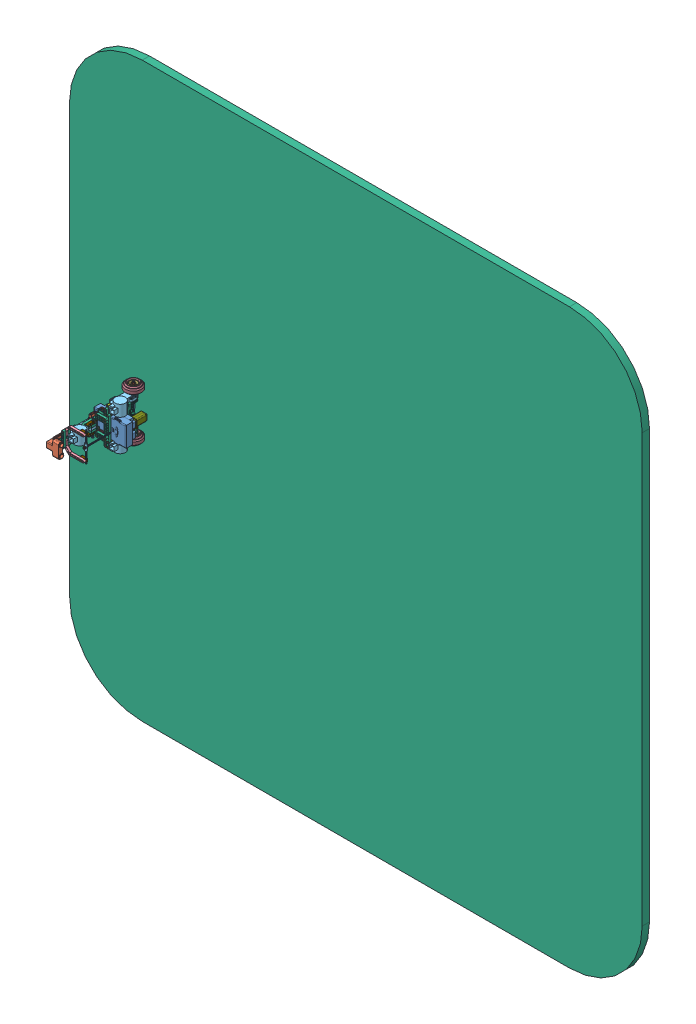
SolidWorks assembly Segway assembly, configuration Default. Lengths in mm.
Overall size (2000 2000 305.82).
138 component instances, 24 part files, 47 mates.
Components (placement in the parent):
- CPU-1: CPU [Default] at (208.205 65.6527 -35.0694) x (1 0 0) z (0 0 1) size (111.76 70.87 40)
- right_connector-1: right_connector [Default] at (170.132 77.851 -11.684) x (0 1 0) z (1 0 0) size (23.11 39.12 23.37)
  - L_Three_Five_90degrees-1: L_Three_Five_90degrees [Default] x (0 1 0) z (-1 0 0) size (39.12 23.37 7.87)
  - BlackConnectorSmall-1: BlackConnectorSmall [Default] at (0 7.874 0) x (-1 0 0) z (0 0 -1) size (15.24 5.59 5.59)
  - BlackConnectorSmall-2: BlackConnectorSmall [Default] at (7.874 -23.622 0) x (-1 0 0) z (0 0 -1) size (15.24 5.59 5.59)
  - BlueConnectorLong-1: BlueConnectorLong [Default] at (7.874 -7.874 0) x (-1 0 0) z (0 0 -1) size (22.86 5.59 5.59)
- left_connector-1: left_connector [Default] at (170.132 -0.889 -11.684) x (0 1 0) z (1 0 0) size (23.11 39.12 23.37)
  - L_Three_Five_90degrees-1: L_Three_Five_90degrees [Default] x (0 1 0) z (-1 0 0) size (39.12 23.37 7.87)
  - BlackConnectorSmall-1: BlackConnectorSmall [Default] at (-7.366 7.874 0) size (15.24 5.59 5.59)
  - BlackConnectorSmall-2: BlackConnectorSmall [Default] at (-15.24 -23.622 0) size (15.24 5.59 5.59)
  - BlueConnectorLong-1: BlueConnectorLong [Default] at (-15.24 -7.874 0) size (22.86 5.59 5.59)
- Motor-1: Motor [Default] at (170.132 -24.257 -19.558) x (0 0 1) z (1 0 0) size (103.9 39.37 46.48)
- Motor-2: Motor [Default] at (170.132 85.979 -19.558) x (0 0 1) z (1 0 0) size (103.9 39.37 46.48)
- horizontal_connector-1: horizontal_connector [Default] at (185.88 34.798 0.127) x (0 1 0) z (1 0 0) size (133.6 31.24 39.12)
  - All_Straight-1: All_Straight [Eleven] at (31.496 0 0) x (1 0 0) z (0 1 0) size (86.36 7.62 7.87)
  - BlackConnectorSmall-1: BlackConnectorSmall [Default] at (39.37 7.62 0) x (0 -1 0) z (0 0 1) size (15.24 5.59 5.59)
  - BlackConnectorSmall-2: BlackConnectorSmall [Default] at (-39.37 7.62 0) x (0 -1 0) z (0 0 1) size (15.24 5.59 5.59)
  - BlackConnectorSmall-4: BlackConnectorSmall [Default] at (-23.622 0.254 0) x (0 1 0) z (0 0 -1) size (15.24 5.59 5.59)
  - BlackConnectorSmall-5: BlackConnectorSmall [Default] at (23.622 0.254 0) x (0 1 0) z (0 0 -1) size (15.24 5.59 5.59)
  - L_Two_Four_90degrees-1: L_Two_Four_90degrees [Default] at (47.4776 -6.6697 -16.0899) x (1 0 0) z (0 -1 0) size (31.24 15.49 7.87)
  - L_Two_Four_90degrees-3: L_Two_Four_90degrees [Default] at (-47.4776 -1.2043 -16.0899) x (-1 0 0) z (0 1 0) size (31.24 15.49 7.87)
  - BlackConnectorSmall-6: BlackConnectorSmall [Default] at (-39.37 -7.62 -7.874) x (0 1 0) z (0 0 -1) size (15.24 5.59 5.59)
  - BlackConnectorSmall-7: BlackConnectorSmall [Default] at (39.37 -7.62 -7.874) x (0 1 0) z (0 0 -1) size (15.24 5.59 5.59)
  - BlueConnectorLong-1: BlueConnectorLong [Default] at (47.244 7.62 -7.874) x (0 -1 0) z (-1 0 0) size (22.86 5.59 5.59)
  - BlueConnectorLong-2: BlueConnectorLong [Default] at (55.118 7.62 -7.874) x (0 -1 0) z (-1 0 0) size (22.86 5.59 5.59)
  - BlueConnectorLong-3: BlueConnectorLong [Default] at (-47.244 7.62 -7.874) x (0 -1 0) z (0 0 1) size (22.86 5.59 5.59)
  - BlueConnectorLong-4: BlueConnectorLong [Default] at (-55.118 7.62 -7.874) x (0 -1 0) z (0 0 1) size (22.86 5.59 5.59)
  - All_Straight-3: All_Straight [Fifteen] at (47.244 0 -7.874) x (1 0 0) z (0 1 0) size (117.86 7.62 7.87)
  - BlackConnectorSmall-8: BlackConnectorSmall [Default] at (23.622 0.254 -7.874) x (0 1 0) z (0 0 -1) size (15.24 5.59 5.59)
  - BlackConnectorSmall-9: BlackConnectorSmall [Default] at (-23.622 0.254 -7.874) x (0 1 0) z (0 0 -1) size (15.24 5.59 5.59)
  - All_Straight-4: All_Straight [Five] at (-23.622 15.748 -7.874) x (0 0 1) z (0 -1 0) size (39.12 7.62 7.87)
  - All_Straight-5: All_Straight [Five] at (23.622 15.748 -7.874) x (0 0 1) z (0 -1 0) size (39.12 7.62 7.87)
  - BlueConnectorCross_Tube-1: BlueConnectorCross_Tube [Default] at (62.992 -7.874 -7.874) x (0 -1 0) z (0 0 1) size (15.24 5.08 5.08)
  - BlueConnectorCross_Tube-2: BlueConnectorCross_Tube [Default] at (-62.992 -7.874 -7.874) x (0 -1 0) z (0 0 -1) size (15.24 5.08 5.08)
- Rotor-1: Rotor [Default] at (178.006 97.155 -90.424) x (-0.695581 0 -0.718448) z (0 1 0) size (23.62 23.62 23.66)
- Rotor-2: Rotor [Default] at (178.006 -13.081 -90.424) x (-0.059852 0 -0.998207) z (0 1 0) size (23.62 23.62 23.66)
- wheel_and_axle-1: wheel_and_axle [Default] at (179.0661 128.27 -89.3291) x (0 -1 0) z (0.695581 0 0.718448) size (82.68 55.88 55.88)
  - CrossTemplate-1: CrossTemplate [Nine] x (0 0 -1) z (1 0 0) size (4.57 4.57 70.87)
  - Light_Gray_X8__Template-1: Light_Gray_X8__Template [one] at (2.54 0 6.35) x (0 0 -1) z (1 0 0) size (7.62 7.62 7.87)
  - Light_Gray_X12-1: Light_Gray_X12 [Rim] at (16.637 0 -9.144) x (0 0 1) z (-1 0 0) size (30.48 30.48 20.07)
  - Light_Gray_X13-1: Light_Gray_X13 [Tire] at (16.637 0 6.096) x (0 0 -1) z (1 0 0) size (55.88 55.88 25.4)
  - Light_Gray_X8__Template-2: Light_Gray_X8__Template [half] at (22.86 0 6.35) x (0 0 -1) z (1 0 0) size (7.62 7.62 3.94)
  - CrossComplementEnd_Small-1: CrossComplementEnd_Small [Three] at (59.054 0 0) x (0 0 -1) z (1 0 0) size (7.62 7.62 23.62)
- wheel_and_axle-2: wheel_and_axle [Default] at (178.0972 -58.674 -88.9027) x (0 1 0) z (0.059852 0 0.998207) size (82.68 55.88 55.88)
  - CrossTemplate-1: CrossTemplate [Nine] x (0 0 -1) z (1 0 0) size (4.57 4.57 70.87)
  - Light_Gray_X8__Template-1: Light_Gray_X8__Template [one] at (2.54 0 6.35) x (0 0 -1) z (1 0 0) size (7.62 7.62 7.87)
  - Light_Gray_X12-1: Light_Gray_X12 [Rim] at (16.637 0 -9.144) x (0 0 1) z (-1 0 0) size (30.48 30.48 20.07)
  - Light_Gray_X13-1: Light_Gray_X13 [Tire] at (16.637 0 6.096) x (0 0 -1) z (1 0 0) size (55.88 55.88 25.4)
  - Light_Gray_X8__Template-2: Light_Gray_X8__Template [half] at (22.86 0 6.35) x (0 0 -1) z (1 0 0) size (7.62 7.62 3.94)
  - CrossComplementEnd_Small-1: CrossComplementEnd_Small [Three] at (59.054 0 0) x (0 0 -1) z (1 0 0) size (7.62 7.62 23.62)
- CrossTemplate-1: CrossTemplate [Five] at (179.1009 54.483 -91.4841) x (-0.718448 0 0.695581) z (0 -1 0) size (4.57 4.57 39.37)
- lower_horizontal_connector-1: lower_horizontal_connector [Default] at (193.754 66.294 -54.991) x (0 1 0) z (1 0 0) size (117.86 51.45 29.62)
  - All_Straight-1: All_Straight [Eleven] x (1 0 0) z (0 1 0) size (86.36 7.62 7.87)
  - BlueConnectorLong-1: BlueConnectorLong [Default] at (7.874 7.493 0) x (0 -1 0) z (0 0 1) size (22.86 5.59 5.59)
  - BlueConnectorLong-2: BlueConnectorLong [Default] at (-70.866 7.493 0) x (0 -1 0) z (0 0 1) size (22.86 5.59 5.59)
  - All_Straight-2: All_Straight [Three] at (7.874 -8.001 0) x (1 0 0) z (0 1 0) size (23.37 7.62 7.87)
  - All_Straight-3: All_Straight [Three] at (-70.866 -8.001 0) x (1 0 0) z (0 1 0) size (23.37 7.62 7.87)
  - Light_Gray_X10-1: Light_Gray_X10 [Default] at (-70.866 -15.621 0) size (31.24 31.24 7.62)
  - Light_Gray_X10-3: Light_Gray_X10 [Default] at (7.874 -15.621 0) x (-1 0 0) z (0 0 -1) size (31.24 31.24 7.62)
  - Light_Gray_X10-4: Light_Gray_X10 [Default] at (-15.748 -8.001 0) size (31.24 31.24 7.62)
  - Light_sensor-1: Light_sensor [Default] at (-31.904 -21.981 14.31) x (-1 0 0) z (0 -1 0) size (22.5 29.62 43.2)
- left_rider_bottom-1: left_rider_bottom [Default] at (142.573 19.05 43.434) x (0 1 0) z (1 0 0) size (39.12 54.99 54.99)
  - All_Straight-1: All_Straight [Seven] x (0 1 0) z (0 0 1) size (54.86 7.62 7.87)
  - BlackConnectorSmall-1: BlackConnectorSmall [Default] at (0 0 15.494) x (0 0 -1) z (1 0 0) size (15.24 5.59 5.59)
  - BlackConnectorSmall-3: BlackConnectorSmall [Default] at (0 -7.874 15.494) x (0 0 -1) z (1 0 0) size (15.24 5.59 5.59)
  - BlackConnectorSmall-4: BlackConnectorSmall [Default] at (0 -23.622 -7.62) x (0 0 1) z (1 0 0) size (15.24 5.59 5.59)
  - BlackConnectorSmall-5: BlackConnectorSmall [Default] at (0 -39.37 -7.62) x (0 0 1) z (1 0 0) size (15.24 5.59 5.59)
  - Light_Gray_X1-1: Light_Gray_X1 [Default] at (3.937 -31.496 -3.937) x (0 1 0) z (0 0 1) size (23.62 23.11 7.87)
  - StraightTurn_Twohole_1Cross-1: StraightTurn_Twohole_1Cross [Default] at (3.81 -7.747 11.811) x (0 -1 0) z (-1 0 0) size (23.5 7.87 7.87)
  - L_Three_Five_90degrees-1: L_Three_Five_90degrees [Default] at (-11.557 -39.37 3.937) x (0 0 -1) z (1 0 0) size (39.12 23.37 7.87)
  - Light_Gray_X1-2: Light_Gray_X1 [Default] at (-19.685 -39.37 19.685) x (0 0 -1) z (0 -1 0) size (23.62 23.11 7.87)
  - BlueConnectorLong-1: BlueConnectorLong [Default] at (-27.305 -39.37 19.685) size (22.86 5.59 5.59)
  - BlackConnectorSmall-6: BlackConnectorSmall [Default] at (-15.748 -27.813 11.811) x (0 -1 0) z (0 0 1) size (15.24 5.59 5.59)
  - BlackConnectorSmall-7: BlackConnectorSmall [Default] at (-15.748 -27.813 27.559) x (0 -1 0) z (0 0 1) size (15.24 5.59 5.59)
  - All_Straight-2: All_Straight [Five] at (-15.748 -35.433 19.685) x (0 0 -1) z (0 1 0) size (39.12 7.62 7.87)
  - All_Straight-3: All_Straight [Three] at (-27.559 -39.37 19.685) x (0 0 -1) z (1 0 0) size (23.37 7.62 7.87)
  - BlackConnectorSmall-8: BlackConnectorSmall [Default] at (-15.748 -43.053 35.433) x (0 1 0) z (0 0 1) size (15.24 5.59 5.59)
  - BlackConnectorSmall-9: BlackConnectorSmall [Default] at (-15.748 -43.053 43.307) x (0 1 0) z (1 0 0) size (15.24 5.59 5.59)
- right_rider_bottom-1: right_rider_bottom [Default] at (142.573 50.546 43.434) x (0 1 0) z (1 0 0) size (39.12 54.99 54.99)
  - All_Straight-1: All_Straight [Seven] x (0 1 0) z (0 0 1) size (54.86 7.62 7.87)
  - BlackConnectorSmall-1: BlackConnectorSmall [Default] at (0 0 15.494) x (0 0 -1) z (1 0 0) size (15.24 5.59 5.59)
  - BlackConnectorSmall-3: BlackConnectorSmall [Default] at (0 -7.874 15.494) x (0 0 -1) z (1 0 0) size (15.24 5.59 5.59)
  - BlackConnectorSmall-4: BlackConnectorSmall [Default] at (0 -23.622 -7.62) x (0 0 1) z (1 0 0) size (15.24 5.59 5.59)
  - BlackConnectorSmall-5: BlackConnectorSmall [Default] at (0 -39.37 -7.62) x (0 0 1) z (1 0 0) size (15.24 5.59 5.59)
  - Light_Gray_X1-1: Light_Gray_X1 [Default] at (3.937 -31.496 -3.937) x (0 1 0) z (0 0 1) size (23.62 23.11 7.87)
  - StraightTurn_Twohole_1Cross-1: StraightTurn_Twohole_1Cross [Default] at (3.81 -7.747 11.811) x (0 -1 0) z (-1 0 0) size (23.5 7.87 7.87)
  - L_Three_Five_90degrees-1: L_Three_Five_90degrees [Default] at (4.191 -39.37 3.937) x (0 0 -1) z (1 0 0) size (39.12 23.37 7.87)
  - Light_Gray_X1-2: Light_Gray_X1 [Default] at (19.685 -39.37 19.685) x (0 0 -1) z (0 1 0) size (23.62 23.11 7.87)
  - BlueConnectorLong-1: BlueConnectorLong [Default] at (27.305 -39.37 19.685) x (-1 0 0) z (0 0 -1) size (22.86 5.59 5.59)
  - BlackConnectorSmall-6: BlackConnectorSmall [Default] at (15.748 -27.813 11.811) x (0 -1 0) z (0 0 1) size (15.24 5.59 5.59)
  - BlackConnectorSmall-7: BlackConnectorSmall [Default] at (15.748 -27.813 27.559) x (0 -1 0) z (0 0 1) size (15.24 5.59 5.59)
  - All_Straight-2: All_Straight [Five] at (15.748 -35.433 19.685) x (0 0 -1) z (0 1 0) size (39.12 7.62 7.87)
  - All_Straight-3: All_Straight [Three] at (27.559 -39.37 19.685) x (0 0 -1) z (-1 0 0) size (23.37 7.62 7.87)
  - BlackConnectorSmall-8: BlackConnectorSmall [Default] at (15.748 -27.813 43.307) x (0 -1 0) z (0 0 1) size (15.24 5.59 5.59)
  - BlackConnectorSmall-9: BlackConnectorSmall [Default] at (15.748 -27.813 35.433) x (0 -1 0) z (0 0 1) size (15.24 5.59 5.59)
- Motor-3: Motor [Default] at (130.762 30.861 82.804) x (0 0 1) z (1 0 0) size (103.9 39.37 46.48)
- Rotor-3: Rotor [Default] at (138.636 42.037 11.938) x (0 0 -1) z (0 1 0) size (23.62 23.62 23.66)
- All_Straight-1: All_Straight [Three] at (154.384 22.987 27.686) x (0 0 -1) z (0 1 0) size (23.37 7.62 7.87)
- BlueConnectorLong-1: BlueConnectorLong [Default] at (154.384 23.241 35.56) x (0 1 0) z (0 0 1) size (22.86 5.59 5.59)
- BlueConnectorLong-2: BlueConnectorLong [Default] at (154.384 46.355 19.812) x (0 -1 0) z (-0.122872 0 0.992423) size (22.86 5.59 5.59)
- All_Straight-2: All_Straight [Three] at (154.384 38.735 27.686) x (0 0 1) z (0 1 0) size (23.37 7.62 7.87)
- CrossTemplateWithCap-1: CrossTemplateWithCap [Eight] at (154.384 4.318 29.21) x (0 0 -1) z (0 1 0) size (6.6 6.6 60.96)
- head-1: head [Default] at (148.2665 34.0473 137.922) x (1 0 0) z (0 -1 0) size (44.45 98.81 50.8)
  - ProximitySensor-1: ProximitySensor [Default] x (1 0 0) z (0 1 0) size (44.45 50.8 27.94)
  - BlueConnectorLong-3: BlueConnectorLong [Default] at (-17.5045 0 10.8063) x (0 0 -1) z (0 -1 0) size (22.86 5.59 5.59)
  - BlueConnectorLong-4: BlueConnectorLong [Default] at (-1.7565 0 -12.3077) x (0 0 1) z (1 0 0) size (22.86 5.59 5.59)
  - L_Three_Five_90degrees-1: L_Three_Five_90degrees [Default] at (-17.5045 -7.874 10.8063) x (0 1 0) z (0 0 -1) size (39.12 23.37 7.87)
  - L_Three_Five_90degrees-3: L_Three_Five_90degrees [Default] at (-17.5045 -7.874 -4.9417) x (0 1 0) z (0 0 -1) size (39.12 23.37 7.87)
  - BlueConnectorLong-5: BlueConnectorLong [Default] at (-17.5045 -7.874 10.8063) x (0 0 -1) z (1 0 0) size (22.86 5.59 5.59)
  - BlueConnectorLong-6: BlueConnectorLong [Default] at (-17.5045 -31.496 -12.3077) x (0 0 1) z (0 -1 0) size (22.86 5.59 5.59)
  - All_Straight-2: All_Straight [Nine] at (-17.5045 -15.748 -4.6877) x (0 1 0) z (0 0 1) size (70.61 7.62 7.87)
- CrossConnectorLong-1: CrossConnectorLong [Default] at (124.7015 15.113 87.8309) x (0.769691 0 -0.638416) z (0 1 0) size (7.62 7.62 23.62)
- CrossConnectorLong-2: CrossConnectorLong [Default] at (124.7015 15.113 72.0829) x (0.769691 0 -0.638416) z (0 1 0) size (7.62 7.62 23.62)
- arms_and_chest-1: arms_and_chest [Default] at (138.636 50.546 117.983) x (0 1 0) z (1 0 0) size (102.11 106.17 70.74)
  - All_Straight-1: All_Straight [Seven] x (1 0 0) z (0 -1 0) size (54.86 7.62 7.87)
  - BlueConnectorLong-1: BlueConnectorLong [Default] at (-39.37 -0.254 0) x (0 -1 0) z (0 0 1) size (22.86 5.59 5.59)
  - BlueConnectorLong-3: BlueConnectorLong [Default] at (7.874 -0.254 0) x (0 -1 0) z (0 0 1) size (22.86 5.59 5.59)
  - BlueConnectorCross_Tube-1: BlueConnectorCross_Tube [Default] at (-23.622 -7.874 0) x (0 1 0) z (0 0 1) size (15.24 5.08 5.08)
  - BlueConnectorCross_Tube-2: BlueConnectorCross_Tube [Default] at (-7.874 -7.874 0) x (0 1 0) z (0 0 1) size (15.24 5.08 5.08)
  - Three_Four_Seven_90degreesTurn-1: Three_Four_Seven_90degreesTurn [Default] at (-31.496 -15.494 0) x (1 0 0) z (0 1 0) size (39.12 70.61 7.62)
  - Three_Four_Seven_90degreesTurn-4: Three_Four_Seven_90degreesTurn [Default] at (0 -7.874 0) x (-1 0 0) z (0 -1 0) size (39.12 70.61 7.62)
  - All_Straight-2: All_Straight [Seven] at (0 -23.368 0) x (1 0 0) z (0 1 0) size (54.86 7.62 7.87)
  - BlackConnectorSmall-1: BlackConnectorSmall [Default] at (23.622 -7.874 47.244) x (0 -1 0) z (0 0 1) size (15.24 5.59 5.59)
  - BlackConnectorSmall-2: BlackConnectorSmall [Default] at (23.622 -7.874 55.118) x (0 -1 0) z (0 0 1) size (15.24 5.59 5.59)
  - BlackConnectorSmall-3: BlackConnectorSmall [Default] at (-55.118 -7.874 47.244) x (0 -1 0) z (0 0 1) size (15.24 5.59 5.59)
  - BlackConnectorSmall-4: BlackConnectorSmall [Default] at (-55.118 -7.874 55.118) x (0 -1 0) z (0 0 1) size (15.24 5.59 5.59)
  - BlackConnectorSmall-5: BlackConnectorSmall [Default] at (-31.496 -23.114 0) x (0 1 0) z (0 0 1) size (15.24 5.59 5.59)
  - BlackConnectorSmall-6: BlackConnectorSmall [Default] at (0 -23.114 0) x (0 1 0) z (0 0 1) size (15.24 5.59 5.59)
  - StraightTurn_Twohole_1Cross-1: StraightTurn_Twohole_1Cross [Default] at (27.432 -19.431 54.991) x (0 0 1) z (-1 0 0) size (23.5 7.87 7.87)
  - StraightTurn_Twohole_1Cross-2: StraightTurn_Twohole_1Cross [Default] at (-51.308 -19.431 54.991) x (0 0 1) z (-1 0 0) size (23.5 7.87 7.87)
  - CrossTemplate-1: CrossTemplate [Six] at (-11.938 -19.431 64.516) x (0 0 -1) z (1 0 0) size (4.57 4.57 47.24)
  - Cross_AngleHole-1: Cross_AngleHole [Default] at (-4.318 -19.431 61.468) x (0 0 1) z (-1 0 0) size (7.62 7.62 22.86)
  - CrossTemplate-2: CrossTemplate [Six] at (-66.802 -19.431 64.516) x (0 0 -1) z (1 0 0) size (4.57 4.57 47.24)
  - CrossTemplate-3: CrossTemplate [Twelve] at (-17.272 -11.684 62.992) x (1 0 0) z (0 -1 0) size (4.57 4.57 94.49)
  - Light_Gray_X8__Template-1: Light_Gray_X8__Template [half] at (-23.622 -11.684 62.992) x (1 0 0) z (0 -1 0) size (7.62 7.62 3.94)
  - BlackConnectorSmall-7: BlackConnectorSmall [Default] at (-7.874 -15.748 0) x (0 -1 0) z (0 0 1) size (15.24 5.59 5.59)
  - BlackConnectorSmall-8: BlackConnectorSmall [Default] at (-23.622 -15.748 0) x (0 -1 0) z (0 0 1) size (15.24 5.59 5.59)
- Tabletop-1: Tabletop [Default] at (-73.175 1085.5214 -118.364) x (1 0 0) z (0 1 0) size (2000 25.4 2000)
Mates (geometry in assembly coordinates):
- Hinge1: hinge anti-aligned: cylinder of right_connector-1/BlackConnectorSmall-1 through (170.132 77.851 -3.81) axis (0 1 0) radius 2.032; cylinder of CPU-1 through (170.132 62.357 -3.81) axis (0 1 0) radius 2.286; plane of CPU-1 through (130 69.596 131.6583) normal (0 1 0); plane of right_connector-1/BlackConnectorSmall-1 through (170.132 69.596 -1.778) normal (0 -1 0)
- Concentric1: concentric anti-aligned: cylinder of CPU-1 through (170.132 66.294 -19.558) axis (0 -1 0) radius 2.54; cylinder of right_connector-1/BlueConnectorLong-1 through (170.132 85.725 -19.558) axis (0 1 0) radius 2.032
- Hinge2: hinge anti-aligned: cylinder of left_connector-1/BlackConnectorSmall-1 through (170.132 -8.255 -3.81) axis (0 -1 0) radius 2.032; cylinder of CPU-1 through (170.132 3.302 -3.81) axis (0 -1 0) radius 2.54; plane of CPU-1 through (130 0 131.6583) normal (0 -1 0); plane of left_connector-1/BlackConnectorSmall-1 through (170.132 0 -1.778) normal (0 1 0)
- Concentric2: concentric aligned: cylinder of CPU-1 through (170.132 3.302 -19.558) axis (0 -1 0) radius 2.54; cylinder of left_connector-1/BlueConnectorLong-1 through (170.132 -16.129 -19.558) axis (0 -1 0) radius 2.032
- Hinge3: hinge anti-aligned: cylinder of left_connector-1/BlueConnectorLong-1 through (170.132 -16.129 -19.558) axis (0 -1 0) radius 2.032; cylinder of Motor-1 through (170.132 -12.446 -19.558) axis (0 -1 0) radius 2.286; plane of left_connector-1/BlueConnectorLong-1 through (170.132 -9.144 -16.764) normal (0 -1 0); plane of Motor-1 through (170.132 -9.144 -19.558) normal (0 1 0)
- Concentric3: concentric aligned: cylinder of left_connector-1/BlackConnectorSmall-2 through (170.132 -16.129 -35.306) axis (0 -1 0) radius 2.032; cylinder of Motor-1 through (170.132 -12.446 -35.306) axis (0 -1 0) radius 2.286
- Hinge4: hinge anti-aligned: cylinder of right_connector-1/BlueConnectorLong-1 through (170.132 85.725 -19.558) axis (0 1 0) radius 2.032; cylinder of Motor-2 through (170.132 82.042 -19.558) axis (0 1 0) radius 2.286; plane of right_connector-1/BlueConnectorLong-1 through (170.132 78.74 -16.764) normal (0 1 0); plane of Motor-2 through (170.132 78.74 -19.558) normal (0 -1 0)
- Concentric4: concentric aligned: cylinder of right_connector-1/BlackConnectorSmall-2 through (170.132 85.725 -35.306) axis (0 1 0) radius 2.032; cylinder of Motor-2 through (170.132 82.042 -35.306) axis (0 1 0) radius 2.286
- Hinge5: hinge anti-aligned: cylinder of horizontal_connector-1/BlueConnectorCross_Tube-2 through (178.006 -28.194 -7.747) axis (0 0 1) radius 2.032; cylinder of Motor-1 through (178.006 -28.194 -11.684) axis (0 0 1) radius 2.286; plane of Motor-1 through (178.006 -28.194 -8.382) normal (0 0 1); plane of horizontal_connector-1/BlueConnectorCross_Tube-2 through (178.006 -30.734 -8.382) normal (0 0 -1)
- Hinge6: hinge anti-aligned: cylinder of horizontal_connector-1/BlueConnectorCross_Tube-1 through (178.006 97.79 -7.747) axis (0 0 1) radius 2.032; cylinder of Motor-2 through (178.006 97.79 -11.684) axis (0 0 1) radius 2.286; plane of Motor-2 through (178.006 97.79 -8.382) normal (0 0 1); plane of horizontal_connector-1/BlueConnectorCross_Tube-1 through (178.006 100.33 -8.382) normal (0 0 -1)
- Hinge7: hinge anti-aligned: cylinder of Rotor-1 through (178.006 79.1397 -90.424) axis (0 1 0) radius 3.81; cylinder of Motor-2 through (178.006 101.727 -90.424) axis (0 -1 0) radius 4.0005; plane of Rotor-1 through (178.006 82.677 -90.424) normal (0 1 0); plane of Motor-2 through (181.689 82.677 -44.5152) normal (0 -1 0)
- Hinge8: hinge anti-aligned: cylinder of Rotor-2 through (178.006 -31.0963 -90.424) axis (0 1 0) radius 3.81; cylinder of Motor-1 through (178.006 -8.509 -90.424) axis (0 -1 0) radius 4.0005; plane of Rotor-2 through (178.006 -13.081 -90.424) normal (0 -1 0); plane of Motor-1 through (181.689 -13.081 -44.5152) normal (0 1 0)
- Concentric6: concentric aligned: cylinder of Rotor-1 through (176.9111 89.916 -89.3639) axis (0 1 0) radius 0.762; cylinder of wheel_and_axle-1/CrossTemplate-1 through (176.9111 57.404 -89.3639) axis (0 1 0) radius 0.762
- Concentric7: concentric aligned: cylinder of Rotor-1 through (176.9459 89.916 -91.5189) axis (0 1 0) radius 0.762; cylinder of wheel_and_axle-1/CrossTemplate-1 through (176.9459 57.404 -91.5189) axis (0 1 0) radius 0.762
- Coincident4: coincident anti-aligned: plane of Rotor-1 through (178.006 101.473 -90.424) normal (0 1 0); plane of wheel_and_axle-1/Light_Gray_X8__Template-2 through (183.483 101.473 -84.7669) normal (0 -1 0)
- Concentric9: concentric anti-aligned: cylinder of Rotor-2 through (179.5273 -20.32 -90.5152) axis (0 1 0) radius 0.762; cylinder of wheel_and_axle-2/CrossTemplate-1 through (179.5273 12.192 -90.5152) axis (0 -1 0) radius 0.762
- Concentric10: concentric anti-aligned: cylinder of Rotor-2 through (177.9148 -20.32 -91.9453) axis (0 1 0) radius 0.762; cylinder of wheel_and_axle-2/CrossTemplate-1 through (177.9148 12.192 -91.9453) axis (0 -1 0) radius 0.762
- Coincident5: coincident anti-aligned: plane of Rotor-2 through (178.006 -31.877 -90.424) normal (0 -1 0); plane of wheel_and_axle-2/Light_Gray_X8__Template-2 through (178.4773 -31.877 -82.5641) normal (0 1 0)
- Width1: width: plane of CPU-1 through (130 0 131.6583) normal (0 -1 0); plane of CPU-1 through (130 69.596 131.6583) normal (0 1 0); plane of CrossTemplate-1; plane of CrossTemplate-1
- Concentric11: concentric aligned: cylinder of wheel_and_axle-1/CrossComplementEnd_Small-1 through (176.9459 45.594 -91.5189) axis (0 1 0) radius 0.762; cylinder of CrossTemplate-1 through (176.9459 15.113 -91.5189) axis (0 1 0) radius 0.762
- Concentric12: concentric aligned: cylinder of wheel_and_axle-1/CrossComplementEnd_Small-1 through (176.9111 45.594 -89.3639) axis (0 1 0) radius 0.762; cylinder of CrossTemplate-1 through (176.9111 15.113 -89.3639) axis (0 1 0) radius 0.762
- Hinge9: hinge anti-aligned: cylinder of lower_horizontal_connector-1/Light_Gray_X10-1 through (193.754 -24.13 -82.55) axis (0 1 0) radius 2.286; cylinder of Motor-1 through (193.754 -20.32 -82.55) axis (0 1 0) radius 2.286; plane of Motor-1 through (193.754 -17.018 -82.55) normal (0 1 0); plane of lower_horizontal_connector-1/Light_Gray_X10-1 through (193.754 -17.018 -82.55) normal (0 -1 0)
- Hinge10: hinge anti-aligned: cylinder of lower_horizontal_connector-1/Light_Gray_X10-3 through (193.754 93.726 -66.802) axis (0 -1 0) radius 2.286; cylinder of Motor-2 through (193.754 89.916 -66.802) axis (0 1 0) radius 2.286; plane of lower_horizontal_connector-1/Light_Gray_X10-3 through (193.754 86.614 -66.802) normal (0 1 0); plane of Motor-2 through (193.754 86.614 -66.802) normal (0 -1 0)
- Hinge11: hinge anti-aligned: cylinder of left_rider_bottom-1/BlackConnectorSmall-9 through (185.88 3.302 0.381) axis (0 0 -1) radius 2.032; cylinder of horizontal_connector-1/All_Straight-1 through (185.88 3.302 4.064) axis (0 0 -1) radius 2.54; plane of horizontal_connector-1/All_Straight-1 through (185.88 3.302 7.366) normal (0 0 1); plane of left_rider_bottom-1/BlackConnectorSmall-9 through (188.674 3.302 7.366) normal (0 0 -1)
- Concentric13: concentric aligned: cylinder of horizontal_connector-1/All_Straight-3 through (178.006 3.302 4.064) axis (0 0 -1) radius 2.54; cylinder of left_rider_bottom-1/BlackConnectorSmall-8 through (178.006 3.302 0.381) axis (0 0 -1) radius 2.032
- Hinge12: hinge anti-aligned: cylinder of right_rider_bottom-1/BlackConnectorSmall-8 through (185.88 66.294 15.621) axis (0 0 1) radius 2.032; cylinder of horizontal_connector-1/All_Straight-1 through (185.88 66.294 4.064) axis (0 0 -1) radius 2.54; plane of horizontal_connector-1/All_Straight-1 through (185.88 66.294 7.366) normal (0 0 1); plane of right_rider_bottom-1/BlackConnectorSmall-8 through (185.88 68.326 7.366) normal (0 0 -1)
- Concentric15: concentric anti-aligned: cylinder of horizontal_connector-1/All_Straight-3 through (178.006 66.294 4.064) axis (0 0 -1) radius 2.54; cylinder of right_rider_bottom-1/BlackConnectorSmall-9 through (178.006 66.294 15.621) axis (0 0 1) radius 2.032
- Hinge13: hinge anti-aligned: cylinder of Rotor-3 through (138.636 24.0217 11.938) axis (0 1 0) radius 3.81; cylinder of Motor-3 through (138.636 46.609 11.938) axis (0 -1 0) radius 4.0005; plane of Motor-3 through (142.319 42.037 57.8468) normal (0 1 0); plane of Rotor-3 through (138.636 42.037 11.938) normal (0 -1 0)
- Hinge14: hinge anti-aligned: cylinder of BlueConnectorLong-1 through (154.384 23.241 35.56) axis (0 -1 0) radius 2.032; cylinder of Motor-3 through (154.384 34.798 35.56) axis (0 1 0) radius 2.286; plane of Motor-3 through (154.384 31.496 35.56) normal (0 -1 0); plane of BlueConnectorLong-1 through (152.352 31.496 35.56) normal (0 1 0)
- Hinge15: hinge anti-aligned: cylinder of All_Straight-1 through (154.384 26.924 35.56) axis (0 -1 0) radius 2.54; cylinder of BlueConnectorLong-1 through (154.384 23.241 35.56) axis (0 -1 0) radius 2.032; plane of BlueConnectorLong-1 through (151.59 30.226 35.56) normal (0 -1 0); plane of All_Straight-1 through (154.384 30.226 35.56) normal (0 1 0)
- Hinge16: hinge anti-aligned: cylinder of BlueConnectorLong-2 through (154.384 46.355 19.812) axis (0 1 0) radius 2.032; cylinder of Motor-3 through (154.384 34.798 19.812) axis (0 1 0) radius 2.286; plane of Motor-3 through (154.384 38.1 19.812) normal (0 1 0); plane of BlueConnectorLong-2 through (156.4006 38.1 20.0617) normal (0 -1 0)
- Hinge17: hinge anti-aligned: cylinder of All_Straight-2 through (154.384 42.672 19.812) axis (0 -1 0) radius 2.54; cylinder of BlueConnectorLong-2 through (154.384 46.355 19.812) axis (0 1 0) radius 2.032; plane of BlueConnectorLong-2 through (157.1568 39.37 20.1553) normal (0 1 0); plane of All_Straight-2 through (154.384 39.37 19.812) normal (0 -1 0)
- Concentric16: concentric aligned: cylinder of BlueConnectorLong-1 through (154.384 23.241 35.56) axis (0 -1 0) radius 2.032; cylinder of All_Straight-2 through (154.384 42.672 35.56) axis (0 -1 0) radius 2.54
- Concentric17: concentric anti-aligned: cylinder of All_Straight-1 through (154.384 26.924 19.812) axis (0 -1 0) radius 2.54; cylinder of BlueConnectorLong-2 through (154.384 46.355 19.812) axis (0 1 0) radius 2.032
- Hinge18: hinge anti-aligned: cylinder of right_rider_bottom-1/Light_Gray_X1-1 through (138.636 38.989 19.812) axis (0 1 0) radius 2.032; cylinder of Rotor-3 through (138.636 46.355 19.812) axis (0 -1 0) radius 2.286; plane of Rotor-3 through (138.636 45.974 19.812) normal (0 1 0); plane of right_rider_bottom-1/Light_Gray_X1-1 through (138.636 45.974 19.812) normal (0 -1 0)
- Concentric18: concentric anti-aligned: cylinder of left_rider_bottom-1/Light_Gray_X1-1 through (138.636 30.607 4.064) axis (0 -1 0) radius 2.032; cylinder of Rotor-3 through (138.636 23.241 4.064) axis (0 1 0) radius 2.286
- Concentric19: concentric anti-aligned: cylinder of CrossTemplateWithCap-1 through (155.908 65.278 27.686) axis (0 -1 0) radius 0.762; cylinder of left_rider_bottom-1/StraightTurn_Twohole_1Cross-1 through (155.908 19.05 27.686) axis (0 1 0) radius 0.762
- Concentric22: concentric anti-aligned: cylinder of left_rider_bottom-1/StraightTurn_Twohole_1Cross-1 through (154.384 19.05 26.162) axis (0 1 0) radius 0.762; cylinder of CrossTemplateWithCap-1 through (154.384 65.278 26.162) axis (0 -1 0) radius 0.762
- Concentric23: concentric anti-aligned: cylinder of Motor-3 through (154.384 34.798 27.686) axis (0 1 0) radius 2.286; circle of CrossTemplateWithCap-1
- Width2: width aligned: plane of left_rider_bottom-1/StraightTurn_Twohole_1Cross-1 through (145.511 15.24 27.7495) normal (0 -1 0); plane of right_rider_bottom-1/StraightTurn_Twohole_1Cross-1 through (145.511 54.356 27.7495) normal (0 1 0); plane of CrossTemplateWithCap-1 through (158.8142 4.318 27.686) normal (0 -1 0); plane of CrossTemplateWithCap-1 through (158.8142 65.278 27.686) normal (0 1 0)
- Hinge19: hinge anti-aligned: cylinder of CrossConnectorLong-1 through (130.762 38.735 82.804) axis (0 -1 0) radius 2.032; cylinder of Motor-3 through (130.762 26.924 82.804) axis (0 1 0) radius 2.286; plane of Motor-3 through (130.762 23.622 82.804) normal (0 -1 0); plane of CrossConnectorLong-1 through (130.762 23.622 82.804) normal (0 1 0)
- Hinge20: hinge anti-aligned: cylinder of Motor-3 through (130.762 26.924 67.056) axis (0 1 0) radius 2.286; cylinder of CrossConnectorLong-2 through (130.762 38.735 67.056) axis (0 -1 0) radius 2.032; plane of Motor-3 through (130.762 23.622 67.056) normal (0 -1 0); plane of CrossConnectorLong-2 through (130.762 23.622 67.056) normal (0 1 0)
- Concentric24: concentric anti-aligned: cylinder of head-1/All_Straight-2 through (130.762 34.798 67.056) axis (0 1 0) radius 2.54; cylinder of CrossConnectorLong-2 through (130.762 38.735 67.056) axis (0 -1 0) radius 2.032
- Concentric25: concentric anti-aligned: cylinder of head-1/All_Straight-2 through (130.762 34.798 82.804) axis (0 1 0) radius 2.54; cylinder of CrossConnectorLong-1 through (130.762 38.735 82.804) axis (0 -1 0) radius 2.032
- Coincident6: coincident anti-aligned: plane of Motor-3 through (155.527 30.861 74.93) normal (0 1 0); plane of head-1/All_Straight-2 through (130.762 30.861 122.174) normal (0 -1 0)
- Hinge21: hinge anti-aligned: cylinder of arms_and_chest-1/BlackConnectorSmall-8 through (138.636 26.924 102.235) axis (0 0 1) radius 2.032; cylinder of Motor-3 through (138.636 26.924 90.678) axis (0 0 1) radius 2.286; plane of Motor-3 through (138.636 26.924 93.98) normal (0 0 1); plane of arms_and_chest-1/BlackConnectorSmall-8 through (138.636 28.956 93.98) normal (0 0 -1)
- Concentric26: concentric aligned: cylinder of Motor-3 through (138.636 42.672 90.678) axis (0 0 1) radius 2.286; cylinder of arms_and_chest-1/BlackConnectorSmall-7 through (138.636 42.672 102.235) axis (0 0 1) radius 2.032
